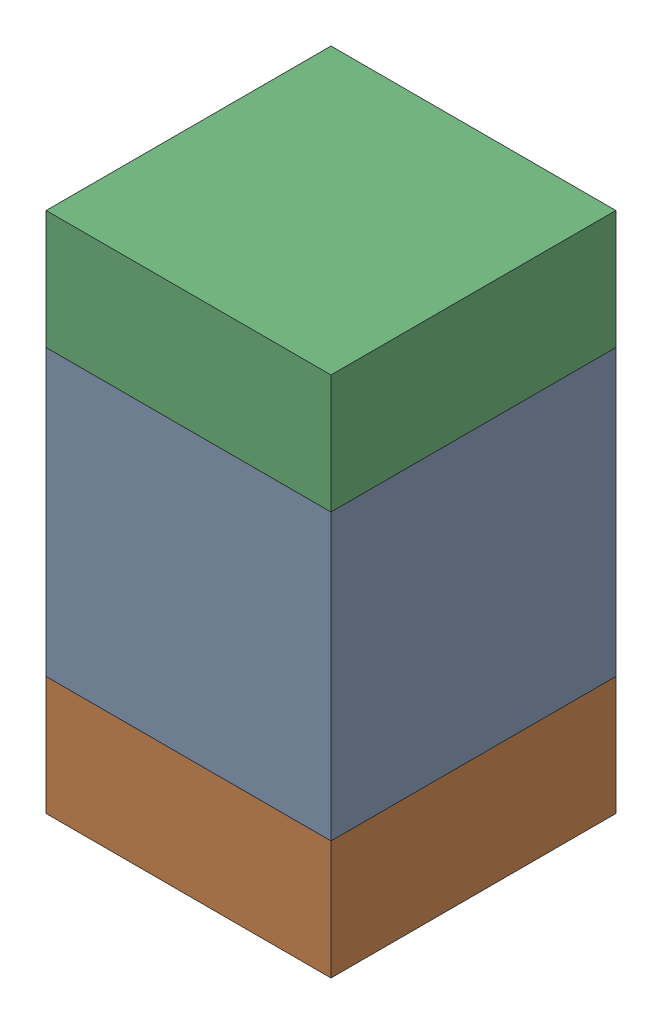
SolidWorks assembly C108_1PCB, configuration Default. Lengths in mm.
Overall size (0.6 1.1 0.6).
6 component instances, 2 part files, 0 mates.
Components (placement in the parent):
- 761606048-1: 761606048 [Default] at (116.7 109.9 0) size (0.6 0.6 0.6)
  - Extruded_9-1: Extruded_9 [Default] at origin size (0.6 0.6 0.6)
- 854785296-1: 854785296 [Default] at (116.7 109.475 0) size (0.6 0.25 0.6)
  - Extruded_10-1: Extruded_10 [Default] at origin size (0.6 0.25 0.6)
- 854785296-2: 854785296 [Default] at (116.7 110.325 0) size (0.6 0.25 0.6)
  - Extruded_10-1: Extruded_10 [Default] at origin size (0.6 0.25 0.6)
